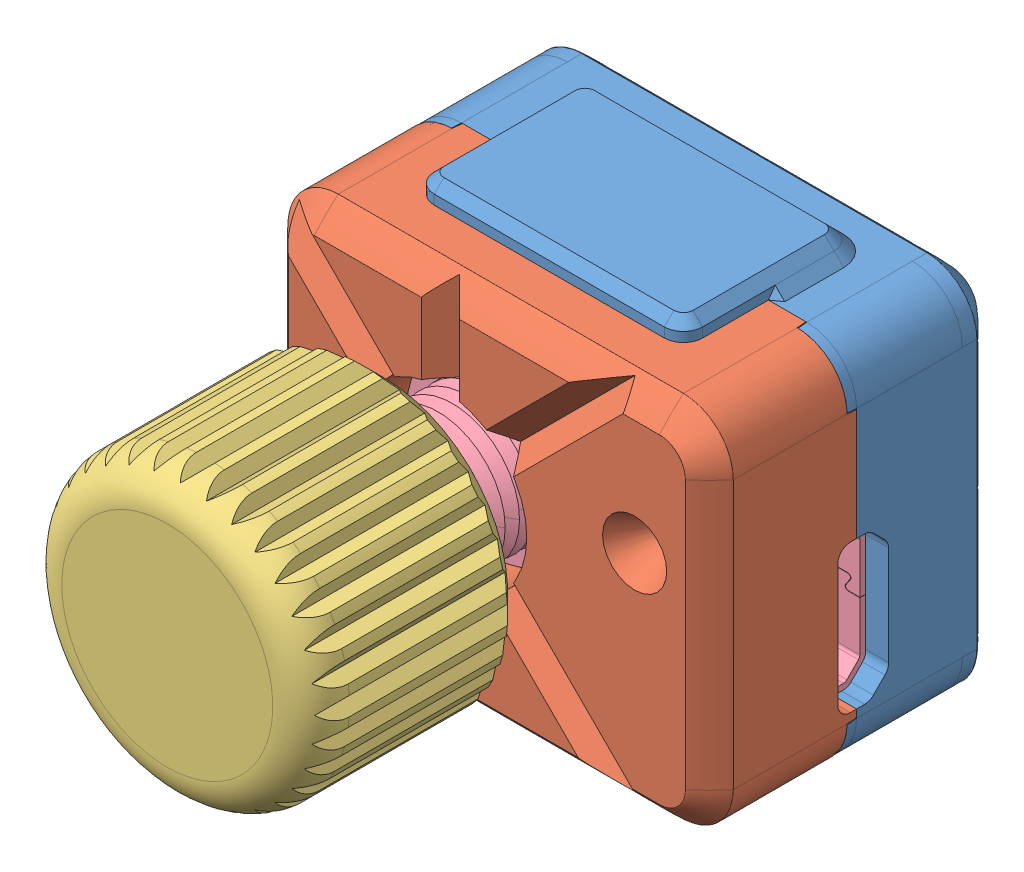
SolidWorks assembly volume_knob, configuration volume_knob. Lengths in mm.
Overall size (23.21 21.2 29.48).
4 component instances, 4 part files, 3 mates.
Components (placement in the parent):
- bottom-1: bottom [bottom] at origin size (23.21 21.2 11.98)
- top-1: top [top] at origin size (23.21 19.21 7.73)
- knob-2: knob [knob] at origin size (15 15 11.25)
- innards-2: innards [innards] at origin size (20.5 16 24.2)
Mates (geometry in assembly coordinates):
- Coincident2: coincident anti-aligned: plane of top-1 through (0 14 2.4108) normal (0 0 -1); plane of bottom-1 through (0 14 2.4108) normal (0 0 1)
- Coincident3: coincident aligned: line of bottom-1 through (-2.6 14 2.4108) axis (0 -1 0); line of top-1 through (-2.6 13.9563 2.4108) axis (0 -1 0)
- Coincident4: coincident aligned: circle of bottom-1; circle of top-1
